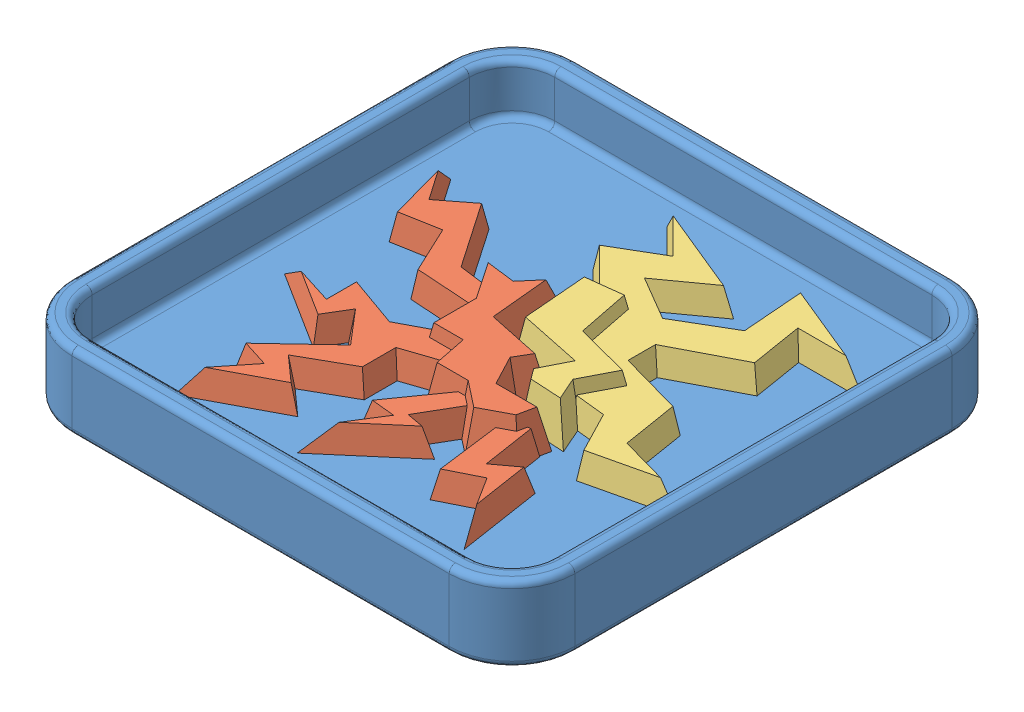
SolidWorks assembly IonStorm, configuration Default. Lengths in mm.
Overall size (40 6 40).
3 component instances, 3 part files, 4 mates.
Components (placement in the parent):
- Tile-1: Tile [Default] at (9.6755 17.7525 33.5593) size (40 6 40)
- IonStorm-1: IonStorm [Default] at (9.7113 19.7525 33.1593) size (35 3 35)
- IonStorm_B-1: IonStorm_B [Default] at (9.6457 19.7525 33.1593) x (0 0 1) z (-1 0 0) size (35 3 35)
Mates (geometry in assembly coordinates):
- Coincident1: coincident anti-aligned: plane of Tile-1 through (-5.3245 19.7525 48.5593) normal (0 1 0); plane of IonStorm-1 through (9.7113 19.7525 33.1593) normal (0 -1 0)
- Coincident2: coincident anti-aligned: line of Tile-1 through (24.6755 19.7525 15.6593) axis (-1 0 0); line of IonStorm-1 through (-7.7887 19.7525 15.6593) axis (1 0 0)
- Coincident3: coincident anti-aligned: line of IonStorm-1 through (-7.7887 19.7525 15.6593) axis (1 0 0); line of IonStorm_B-1 through (27.1457 19.7525 15.6593) axis (-1 0 0)
- Coincident4: coincident anti-aligned: plane of Tile-1 through (-5.3245 19.7525 48.5593) normal (0 1 0); plane of IonStorm_B-1 through (9.6457 19.7525 33.1593) normal (0 -1 0)
